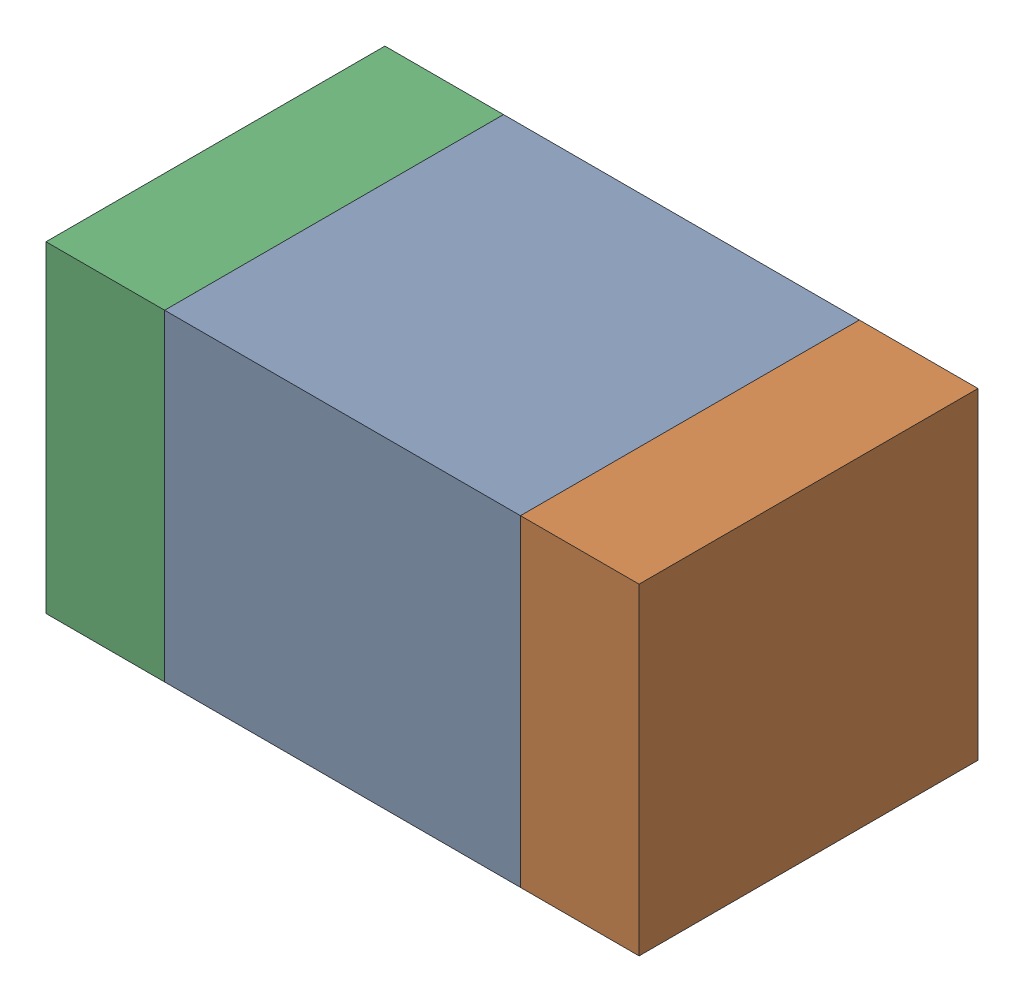
SolidWorks assembly C419PCB, configuration Default. Lengths in mm.
Overall size (1.75 0.95 1).
6 component instances, 2 part files, 0 mates.
Components (placement in the parent):
- 761616112-1: 761616112 [Default] at (117.8 97.3 -2.6638) size (1.05 0.95 1)
  - Extruded_14-1: Extruded_14 [Default] at origin size (1.05 0.95 1)
- 761616248-1: 761616248 [Default] at (118.5 97.3 -2.6638) size (0.35 0.95 1)
  - Extruded_15-1: Extruded_15 [Default] at origin size (0.35 0.95 1)
- 761616248-2: 761616248 [Default] at (117.1 97.3 -2.6638) size (0.35 0.95 1)
  - Extruded_15-1: Extruded_15 [Default] at origin size (0.35 0.95 1)
